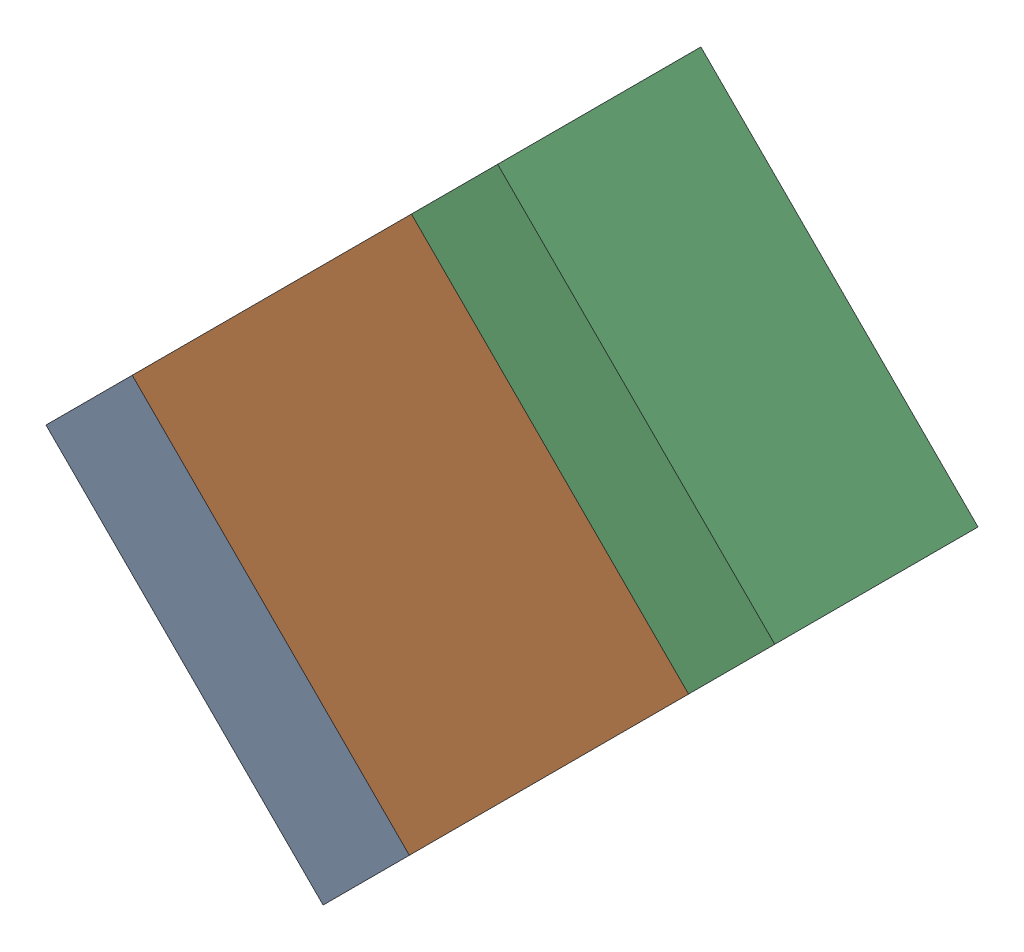
SolidWorks assembly R8, configuration Default. Lengths in mm.
Overall size (2.51 2.51 0.7).
6 component instances, 2 part files, 0 mates.
Components (placement in the parent):
- 959207576-1: 959207576 [Default] at (78.6187 92.1936 0) size (1.25 1.25 0.7)
  - Extruded-23-1: Extruded-23 [Default] at origin size (1.25 1.25 0.7)
- 959207712-1: 959207712 [Default] at (79.248 92.8229 0) size (1.92 1.92 0.7)
  - Extruded-24-1: Extruded-24 [Default] at origin size (1.92 1.92 0.7)
- 959207576-2: 959207576 [Default] at (79.8773 93.4522 0) size (1.25 1.25 0.7)
  - Extruded-23-1: Extruded-23 [Default] at origin size (1.25 1.25 0.7)
